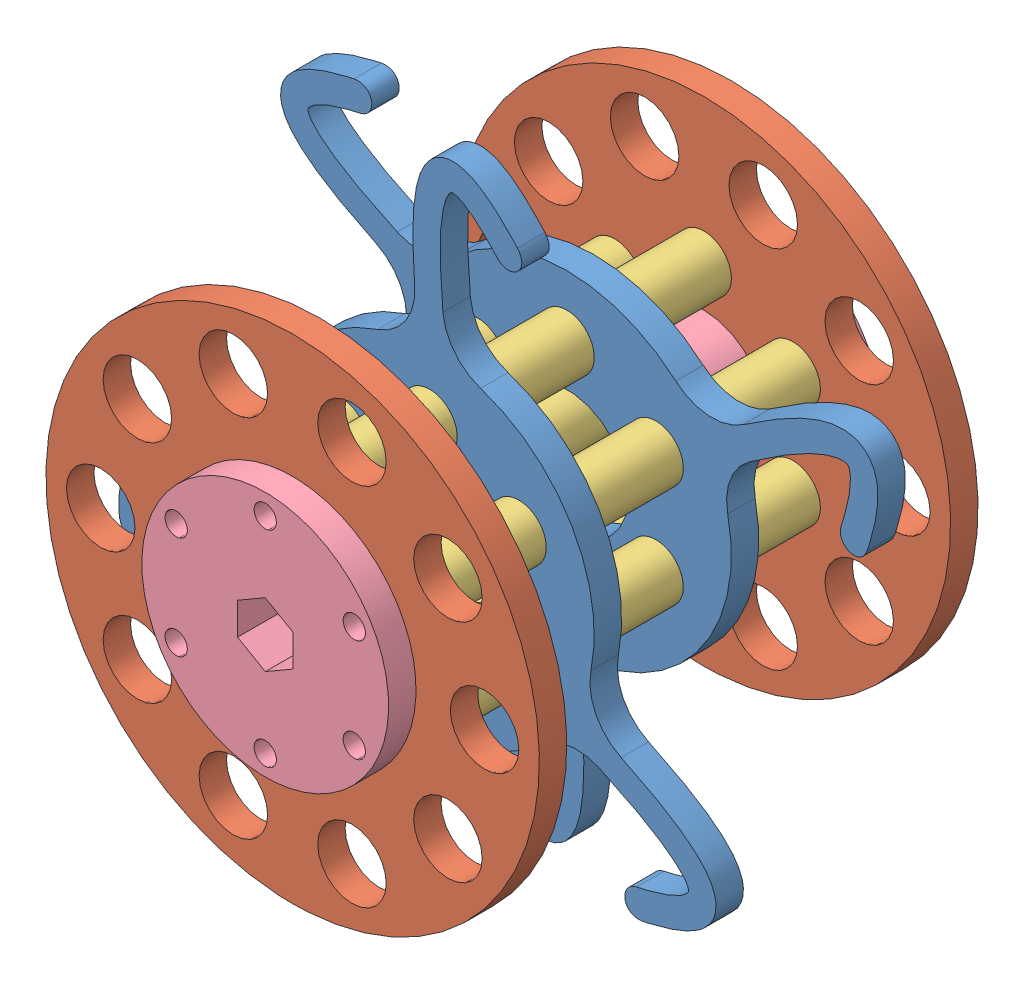
SolidWorks assembly Climber_Assm, configuration Default. Lengths in mm.
Overall size (182.74 185.47 114.3).
24 component instances, 4 part files, 21 mates.
Components (placement in the parent):
- Spoke-1: Spoke [Default] at origin size (138.51 131.05 6.35)
- Spoke-2: Spoke [Default] at (0 0 -31.75) x (0.5 -0.866025 0) z (0 0 1) size (138.51 131.05 6.35)
- End_Plate-1: End_Plate [Default] at (0 0 31.75) x (0 0 1) z (0 1 0) size (6.35 114.3 114.3)
- End_Plate-2: End_Plate [Default] at (0 0 -63.5) x (0 0 1) z (0 1 0) size (6.35 114.3 114.3)
- Spacer-1: Spacer [Default] at (-20.6222 11.9062 6.35) x (-0.643357 -0.765567 0) z (-0.765567 0.643357 0) size (12.7 25.4 12.7)
- Spacer-2: Spacer [Default] at (0 23.8125 6.35) x (-0.984678 0.17438 0) z (0.17438 0.984678 0) size (12.7 25.4 12.7)
- Spacer-3: Spacer [Default] at (20.6222 11.9062 6.35) x (-0.341322 0.939946 0) z (0.939946 0.341322 0) size (12.7 25.4 12.7)
- Spacer-4: Spacer [Default] at (20.6222 -11.9062 6.35) x (0.643357 0.765567 0) z (0.765567 -0.643357 0) size (12.7 25.4 12.7)
- Spacer-5: Spacer [Default] at (0 -23.8125 6.35) x (0.984678 -0.17438 0) z (-0.17438 -0.984678 0) size (12.7 25.4 12.7)
- Spacer-6: Spacer [Default] at (-20.6222 -11.9062 6.35) x (0.341322 -0.939946 0) z (-0.939946 -0.341322 0) size (12.7 25.4 12.7)
- Spacer-7: Spacer [Default] at (-20.6222 11.9062 -25.4) x (-0.643357 -0.765567 0) z (-0.765567 0.643357 0) size (12.7 25.4 12.7)
- Spacer-8: Spacer [Default] at (-20.6222 11.9062 -57.15) x (-0.643357 -0.765567 0) z (-0.765567 0.643357 0) size (12.7 25.4 12.7)
- Spacer-10: Spacer [Default] at (0 23.8125 -25.4) x (-0.984678 0.17438 0) z (0.17438 0.984678 0) size (12.7 25.4 12.7)
- Spacer-11: Spacer [Default] at (0 23.8125 -57.15) x (-0.984678 0.17438 0) z (0.17438 0.984678 0) size (12.7 25.4 12.7)
- Spacer-13: Spacer [Default] at (20.6222 11.9062 -25.4) x (-0.341322 0.939946 0) z (0.939946 0.341322 0) size (12.7 25.4 12.7)
- Spacer-14: Spacer [Default] at (20.6222 11.9062 -57.15) x (-0.341322 0.939946 0) z (0.939946 0.341322 0) size (12.7 25.4 12.7)
- Spacer-16: Spacer [Default] at (20.6222 -11.9062 -25.4) x (0.643357 0.765567 0) z (0.765567 -0.643357 0) size (12.7 25.4 12.7)
- Spacer-17: Spacer [Default] at (20.6222 -11.9062 -57.15) x (0.643357 0.765567 0) z (0.765567 -0.643357 0) size (12.7 25.4 12.7)
- Spacer-19: Spacer [Default] at (0 -23.8125 -25.4) x (0.984678 -0.17438 0) z (-0.17438 -0.984678 0) size (12.7 25.4 12.7)
- Spacer-20: Spacer [Default] at (0 -23.8125 -57.15) x (0.984678 -0.17438 0) z (-0.17438 -0.984678 0) size (12.7 25.4 12.7)
- Spacer-22: Spacer [Default] at (-20.6222 -11.9062 -25.4) x (0.341322 -0.939946 0) z (-0.939946 -0.341322 0) size (12.7 25.4 12.7)
- Spacer-23: Spacer [Default] at (-20.6222 -11.9062 -57.15) x (0.341322 -0.939946 0) z (-0.939946 -0.341322 0) size (12.7 25.4 12.7)
- Hub-1: Hub [Default] at (0 0 -63.5) x (-1 0 0) z (0 0 -1) size (57.15 57.15 25.4)
- Hub-2: Hub [Default] at (0 0 38.1) x (0.5 0.866025 0) z (0 0 1) size (57.15 57.15 25.4)
Mates (geometry in assembly coordinates):
- InPlace1: in place: plane of Spoke-1 through (0 0 0) normal (0 0 1); moOrthogonalPlaneRef_w of Spoke-1 through (0 0 0) normal (0 1 0); plane of Spoke-1 through (0 0 0) normal (1 0 0); unknown of Spoke-1
- Coincident1: coincident aligned: plane of Spoke-1; plane of assembly
- Coincident2: coincident aligned: plane of Spoke-1 through (0 0 0) normal (0 1 0); moOrthogonalPlaneRef_w of assembly
- Coincident3: coincident anti-aligned: plane of Spoke-1 through (0 0 0) normal (1 0 0); moOrthogonalPlaneRef_w of assembly
- Distance1: distance = 25.4 mm anti-aligned: plane of Spoke-1 through (0 0 0) normal (0 0 -1); plane of Spoke-2 through (0 0 -25.4) normal (0 0 1)
- Concentric1: concentric aligned: cylinder of Spoke-1 through (0 0 -0.001) axis (0 0 1) radius 14.2875; cylinder of Spoke-2 through (0 0 -31.751) axis (0 0 1) radius 14.2875
- Concentric2: concentric aligned: cylinder of Spoke-1 through (20.6222 11.9062 -0.001) axis (0 0 1) radius 2.54; cylinder of Spoke-2 through (20.6222 11.9062 -31.751) axis (0 0 1) radius 2.54
- Concentric4: concentric anti-aligned: cylinder of Spoke-1 through (0 0 -0.001) axis (0 0 1) radius 14.2875; cylinder of End_Plate-1 through (0 0 38.1) axis (0 0 -1) radius 14.2875
- Parallel1: parallel aligned: line of Spoke-1 through (0 0 6.35) axis (1 0 0); line of End_Plate-1 through (0 0 38.1) axis (1 0 0)
- Distance3: distance = 25.4 mm anti-aligned: plane of End_Plate-1 through (0 0 31.75) normal (0 0 -1); plane of Spoke-1 through (0 0 6.35) normal (0 0 1)
- Concentric5: concentric aligned: cylinder of End_Plate-1 through (0 0 38.1) axis (0 0 -1) radius 14.2875; cylinder of End_Plate-2 through (0 0 -57.15) axis (0 0 -1) radius 14.2875
- Coincident7: coincident aligned: circle of End_Plate-1; cylinder of End_Plate-2 through (0 23.8125 -57.149) axis (0 0 -1) radius 2.54
- Coincident8: coincident anti-aligned: plane of End_Plate-1 through (0 0 31.75) normal (0 0 -1); plane of Spacer-1 through (-20.6222 11.9062 31.75) normal (0 0 1)
- Concentric6: concentric aligned: cylinder of End_Plate-1 through (-20.6222 11.9062 38.101) axis (0 0 -1) radius 2.54; cylinder of Spacer-1 through (-20.6222 11.9062 31.75) axis (0 0 -1) radius 3.175
- Coincident9: coincident anti-aligned: plane of End_Plate-2 through (0 0 -63.5) normal (0 0 -1); plane of Hub-1 through (0 0 -63.5) normal (0 0 1)
- Concentric8: concentric anti-aligned: cylinder of End_Plate-2 through (0 0 -57.15) axis (0 0 -1) radius 14.2875; cylinder of Hub-1 through (0 0 -69.85) axis (0 0 1) radius 28.575
- Concentric9: concentric anti-aligned: cylinder of End_Plate-2 through (-20.6222 -11.9062 -57.149) axis (0 0 -1) radius 2.54; cylinder of Hub-1 through (-20.6222 -11.9062 -69.85) axis (0 0 1) radius 2.5908
- Coincident10: coincident anti-aligned: plane of End_Plate-1 through (0 0 38.1) normal (0 0 1); plane of Hub-2 through (0 0 38.1) normal (0 0 -1)
- Concentric10: concentric aligned: cylinder of End_Plate-1 through (0 0 38.1) axis (0 0 -1) radius 14.2875; cylinder of Hub-2 through (0 0 44.45) axis (0 0 -1) radius 28.575
- Concentric11: concentric aligned: cylinder of End_Plate-1 through (0 23.8125 38.101) axis (0 0 -1) radius 2.54; cylinder of Hub-2 through (0 23.8125 44.45) axis (0 0 -1) radius 2.5908
- Coincident11: coincident anti-aligned: plane of End_Plate-2 through (0 0 -57.15) normal (0 0 1); plane of Spacer-11 through (0 23.8125 -57.15) normal (0 0 -1)
